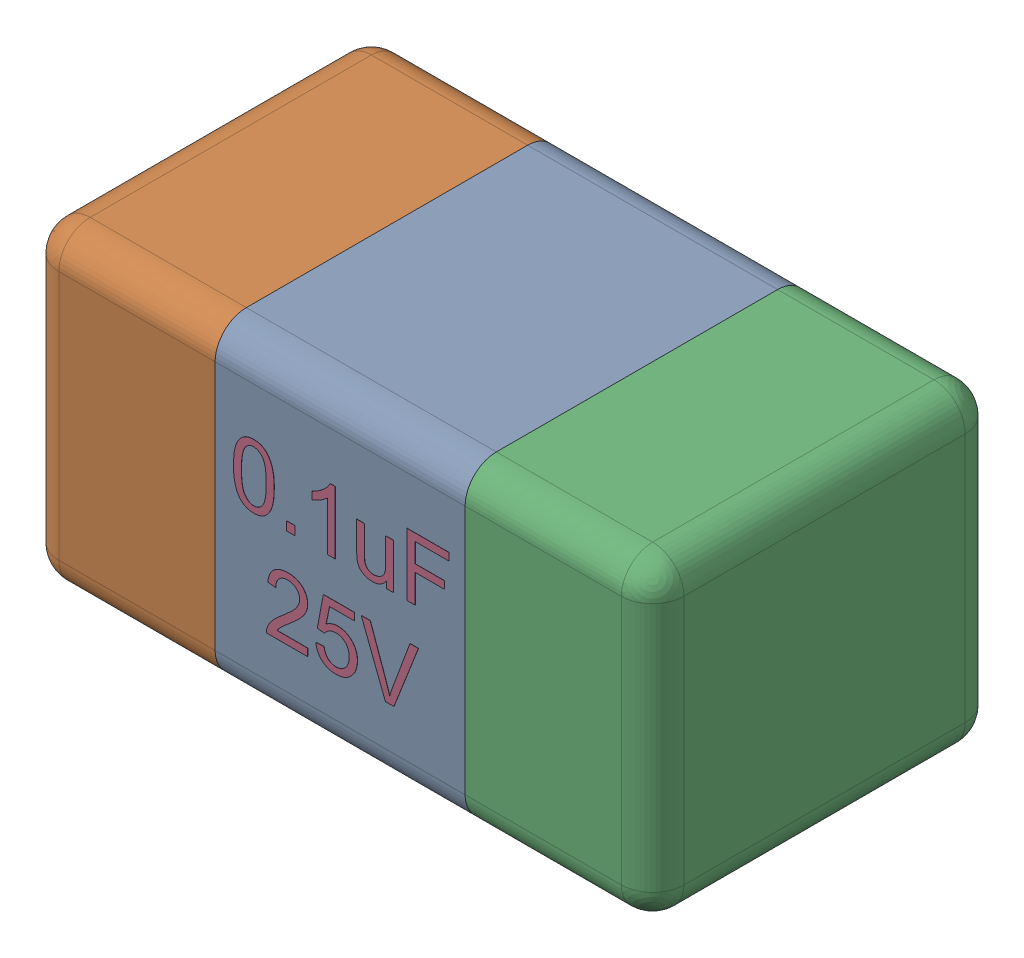
SolidWorks assembly Cap_Kemet_C0402C562J5RACTU_eec, configuration Default. Lengths in mm.
Overall size (1.01 0.51 0.56).
4 component instances, 4 part files, 0 mates.
Components (placement in the parent):
- body_2-1: body_2 [Default] at origin size (0.4 0.5 0.55)
- terminals-1: terminals [Default] at origin size (0.31 0.51 0.56)
- terminals_2-1: terminals_2 [Default] at origin size (0.31 0.51 0.56)
- value-1: value [Default] at (0 0 0.55) size (0.37 0.29 0.15)
